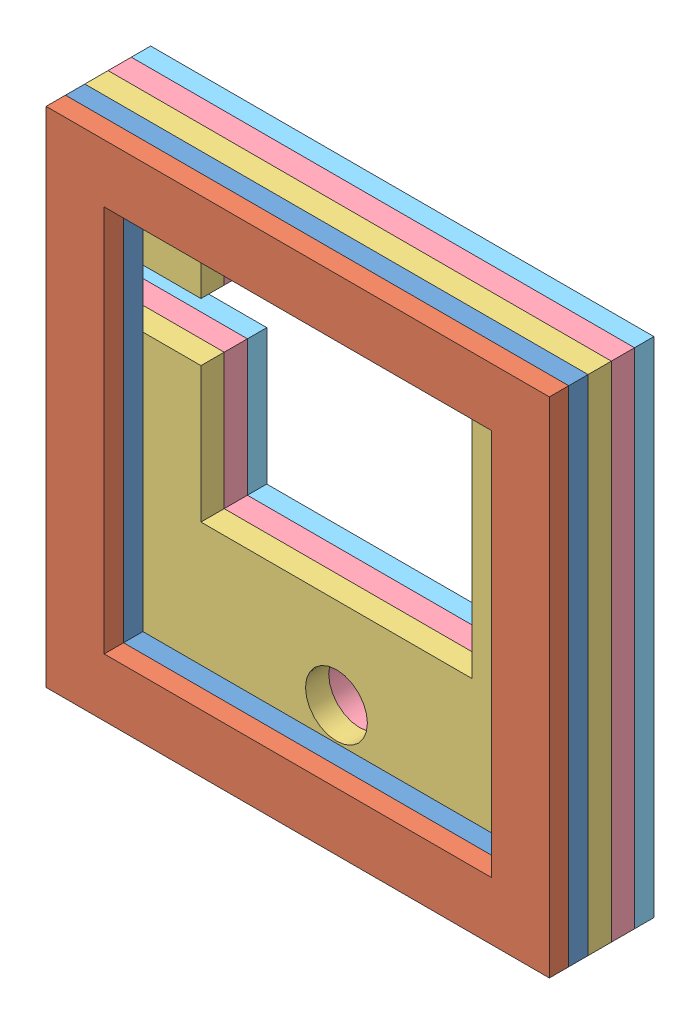
SolidWorks assembly Assieme1, configuration Default. Lengths in mm.
Overall size (130 130 27).
5 component instances, 5 part files, 12 mates.
Components (placement in the parent):
- strato 1-1: strato 1 [Default] at (4.3675 -0.9827 127.5) size (130 130 5)
- strato 2-1: strato 2 [Default] at (4.3675 -0.9827 132.5) size (130 130 5)
- strato3-1: strato3 [Default] at (4.3675 -0.9827 121.5) size (130 130 6)
- strato4 - Copia-1: strato4 - Copia [Default] at (4.3675 -0.9827 115.5) size (130 130 6)
- strato5-1: strato5 [Default] at (4.3675 -0.9827 110.5) size (130 130 5)
Mates (geometry in assembly coordinates):
- Coincidente1: coincident: plane of strato 1-1 through (4.3675 -0.9827 132.5) normal (0 0 1); plane of strato 2-1 through (4.3675 -0.9827 132.5) normal (0 0 -1)
- Coincidente2: coincident: plane of strato 1-1 through (-60.6325 64.0173 132.5) normal (-1 0 0); plane of strato 2-1 through (-60.6325 64.0173 137.5) normal (-1 0 0)
- Coincidente3: coincident aligned: plane of strato 1-1 through (69.3675 64.0173 132.5) normal (0 1 0); plane of strato 2-1 through (69.3675 64.0173 137.5) normal (0 1 0)
- Coincidente4: coincident: plane of strato 1-1 through (4.3675 -0.9827 127.5) normal (0 0 -1); plane of strato3-1 through (4.3675 -0.9827 127.5) normal (0 0 1)
- Coincidente5: coincident: plane of strato 1-1 through (-60.6325 64.0173 132.5) normal (-1 0 0); plane of strato3-1 through (-60.6325 -65.9827 127.5) normal (-1 0 0)
- Coincidente6: coincident aligned: plane of strato 1-1 through (69.3675 -65.9827 132.5) normal (0 -1 0); plane of strato3-1 through (69.3675 -65.9827 127.5) normal (0 -1 0)
- Coincidente7: coincident: plane of strato3-1 through (4.3675 -0.9827 121.5) normal (0 0 -1); plane of strato4 - Copia-1 through (4.3675 -0.9827 121.5) normal (0 0 1)
- Coincidente8: coincident: plane of strato3-1 through (69.3675 -65.9827 127.5) normal (1 0 0); plane of strato4 - Copia-1 through (69.3675 -65.9827 121.5) normal (1 0 0)
- Concentrico1: concentric aligned: cylinder of strato3-1 through (4.3675 -42.4827 112.5) axis (0 0 1) radius 8; cylinder of strato4 - Copia-1 through (4.3675 -42.4827 106.5) axis (0 0 1) radius 8
- Coincidente9: coincident: plane of strato4 - Copia-1 through (4.3675 -0.9827 115.5) normal (0 0 -1); plane of strato5-1 through (4.3675 -0.9827 115.5) normal (0 0 1)
- Coincidente10: coincident: plane of strato4 - Copia-1 through (69.3675 -65.9827 121.5) normal (1 0 0); plane of strato5-1 through (69.3675 -65.9827 115.5) normal (1 0 0)
- Coincidente11: coincident aligned: plane of strato4 - Copia-1 through (69.3675 64.0173 121.5) normal (0 1 0); plane of strato5-1 through (69.3675 64.0173 115.5) normal (0 1 0)
